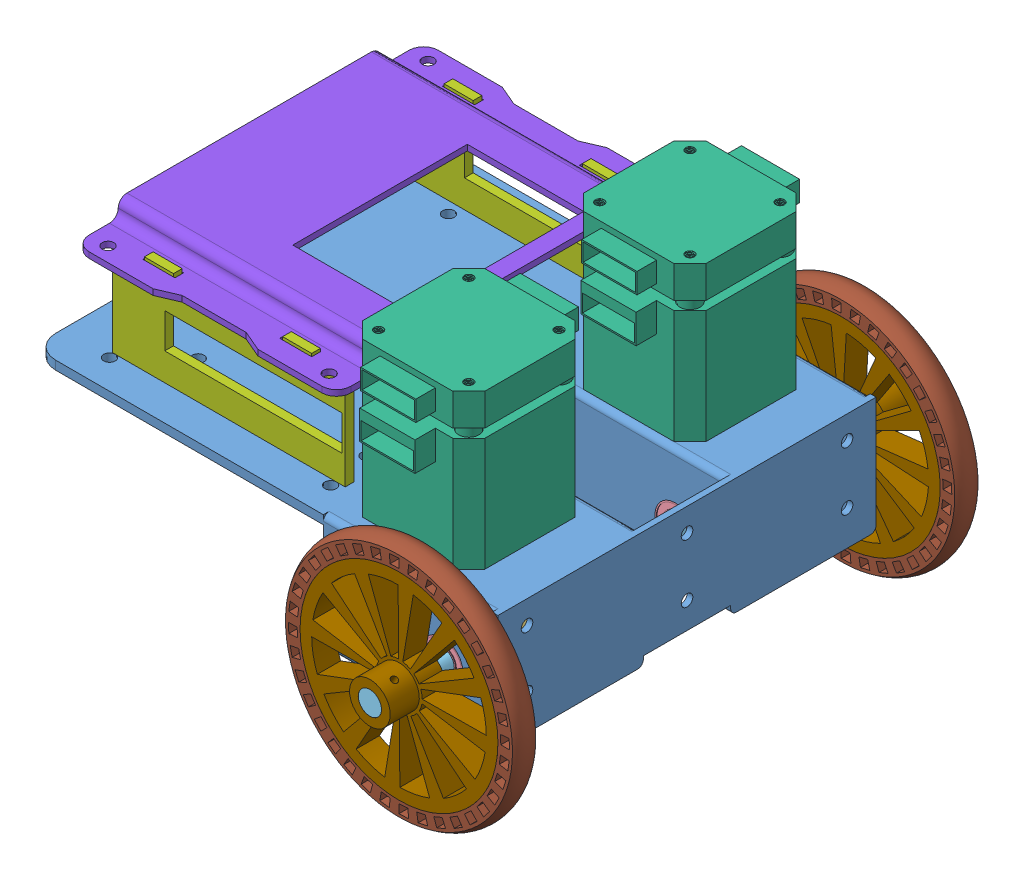
SolidWorks assembly JetBot, configuration 默认. Lengths in mm.
Overall size (187.31 122.31 180).
21 component instances, 11 part files, 44 mates.
Components (placement in the parent):
- Part_Frame_42Motor-1: Part_Frame_42Motor [默认] at (-18.89 -6.9833 215) size (160 40 130)
- Part_Shaft_1Modulus_1Teeth_42SMotor-1: Part_Shaft_1Modulus_1Teeth_42SMotor [默认] at (4.11 0.0167 268) x (0 1 0) z (0.917431 0 0.397896) size (33.1 17.69 17.84)
- Part_Turbine_1Modulus_20Teeth_42SMotor-1: Part_Turbine_1Modulus_20Teeth_42SMotor [默认] at (22.11 10.0167 197.3769) x (0.249686 -0.968327 0) z (0.968327 0.249686 0) size (29.84 18 44.58)
- Part_Shaft_1Modulus_1Teeth_42SMotor-2: Part_Shaft_1Modulus_1Teeth_42SMotor [默认] at (4.11 0.0167 192) x (0 1 0) z (0 0 1) size (33.1 17.69 17.84)
- Part_Turbine_1Modulus_20Teeth_42SMotor-2: Part_Turbine_1Modulus_20Teeth_42SMotor [默认] at (22.11 10.0167 262.7715) x (-0.761731 -0.647894 0) z (-0.647894 0.761731 0) size (29.84 18 44.58)
- Part_Bearing_MR148ZZ-1: Part_Bearing_MR148ZZ [默认] at (22.11 10.0167 249) x (0 0 -1) z (-0.338993 0.940789 0) size (4 14 14)
- Part_Bearing_MR148ZZ-2: Part_Bearing_MR148ZZ [默认] at (22.11 10.0167 215) x (0 0 -1) z (0.782637 0.622478 0) size (4 14 14)
- Part_Bearing_MR148ZZ-3: Part_Bearing_MR148ZZ [默认] at (22.11 10.0167 165) x (0 0 1) z (-0.469267 0.883056 0) size (4 14 14)
- Part_Bearing_MR148ZZ-4: Part_Bearing_MR148ZZ [默认] at (22.11 10.0167 291) x (0 0 1) z (-0.560257 0.828319 0) size (4 14 14)
- Part_Axis_8mm_Turbine_Wheel-1: Part_Axis_8mm_Turbine_Wheel [默认] at (22.11 10.0167 140) x (-0.226706 -0.973963 0) z (0 0 1) size (8 17.7 80)
- Part_Axis_8mm_Turbine_Wheel-2: Part_Axis_8mm_Turbine_Wheel [默认] at (22.11 10.0167 320) x (-0.923728 -0.383049 0) z (0 0 -1) size (8 17.7 80)
- Part_42Motor-2: Part_42Motor [默认] at (25.11 86.0167 213) x (-1 0 0) z (0 0 1) size (42 76 55.7)
- Part_Shell_Side_Frame-1: Part_Shell_Side_Frame [默认] at (-23.39 64.0167 177) x (-1 0 0) z (0 0 1) size (80 37 3)
- Part_Shell_Side_Frame-2: Part_Shell_Side_Frame [默认] at (-23.39 64.0167 280) x (-1 0 0) z (0 0 1) size (80 37 3)
- Part_Shell_Top_Frame-1: Part_Shell_Top_Frame [默认] at (-19.39 70.0167 230) x (0 0 1) z (-1 0 0) size (120 8 90)
- Part_42Motor-3: Part_42Motor [默认] at (25.11 86.0167 289) x (-1 0 0) z (0 0 1) size (42 76 55.7)
- Part_Wheel_Motor-1: Part_Wheel_Motor [默认] at (22.11 10.0167 306) x (0.490908 0.871211 0) z (0 0 1) size (68 68 18)
- Part_Wheel_Motor-2: Part_Wheel_Motor [默认] at (22.11 10.0167 154) x (-0.998325 0.057848 0) z (0 0 -1) size (68 68 18)
- Part_Wheel_Universal-1: Part_Wheel_Universal [默认] at (-81.89 -6.9833 230) x (0 0 -1) z (-1 0 0) size (28 21 48)
- Part_Tires_Wheel-1: Part_Tires_Wheel [默认] at (22.11 10.0167 306) size (80.81 80.81 8)
- Part_Tires_Wheel-2: Part_Tires_Wheel [默认] at (22.11 10.0167 154) size (80.81 80.81 8)
Mates (geometry in assembly coordinates):
- 同心2: concentric anti-aligned: cylinder of Part_Shaft_1Modulus_1Teeth_42SMotor-2 through (4.11 30.0167 192) axis (0 -1 0) radius 2.5; cylinder of Part_42Motor-2 through (4.11 10.0167 192) axis (0 1 0) radius 2.5
- 距离1: distance = 3 mm anti-aligned: plane of Part_Shaft_1Modulus_1Teeth_42SMotor-2 through (4.11 30.0167 192) normal (0 1 0); plane of Part_42Motor-2 through (25.11 33.0167 213) normal (0 -1 0)
- 同心3: concentric anti-aligned: cylinder of Part_Turbine_1Modulus_20Teeth_42SMotor-1 through (22.11 10.0167 187.3769) axis (0 0 1) radius 4; cylinder of Part_Axis_8mm_Turbine_Wheel-1 through (22.11 10.0167 220) axis (0 0 -1) radius 4
- 同心4: concentric anti-aligned: cylinder of Part_Turbine_1Modulus_20Teeth_42SMotor-2 through (22.11 10.0167 272.7715) axis (0 0 -1) radius 4; cylinder of Part_Axis_8mm_Turbine_Wheel-2 through (22.11 10.0167 240) axis (0 0 1) radius 4
- 同心5: concentric anti-aligned: cylinder of Part_Bearing_MR148ZZ-3 through (22.11 10.0167 169) axis (0 0 -1) radius 4; cylinder of Part_Axis_8mm_Turbine_Wheel-2 through (22.11 10.0167 240) axis (0 0 1) radius 4
- 同心6: concentric anti-aligned: cylinder of Part_Bearing_MR148ZZ-4 through (22.11 10.0167 295) axis (0 0 -1) radius 4; cylinder of Part_Axis_8mm_Turbine_Wheel-2 through (22.11 10.0167 240) axis (0 0 1) radius 4
- 同心7: concentric anti-aligned: cylinder of Part_Bearing_MR148ZZ-1 through (22.11 10.0167 245) axis (0 0 1) radius 4; cylinder of Part_Axis_8mm_Turbine_Wheel-1 through (22.11 10.0167 220) axis (0 0 -1) radius 4
- 同心8: concentric anti-aligned: cylinder of Part_Bearing_MR148ZZ-2 through (22.11 10.0167 211) axis (0 0 1) radius 4; cylinder of Part_Axis_8mm_Turbine_Wheel-1 through (22.11 10.0167 220) axis (0 0 -1) radius 4
- 同心9: concentric anti-aligned: cylinder of Part_Frame_42Motor-1 through (22.11 10.0167 165) axis (0 0 1) radius 7; cylinder of Part_Axis_8mm_Turbine_Wheel-1 through (22.11 10.0167 220) axis (0 0 -1) radius 4
- 同心10: concentric aligned: cylinder of Part_Frame_42Motor-1 through (22.11 10.0167 165) axis (0 0 1) radius 7; cylinder of Part_Axis_8mm_Turbine_Wheel-2 through (22.11 10.0167 240) axis (0 0 1) radius 4
- 重合3: coincident anti-aligned: plane of Part_Frame_42Motor-1 through (41.11 33.0167 167) normal (0 1 0); plane of Part_42Motor-2 through (25.11 33.0167 213) normal (0 -1 0)
- 重合5: coincident aligned: plane of Part_Frame_42Motor-1 through (41.11 -4.9833 165) normal (0 0 -1); plane of Part_Bearing_MR148ZZ-3 through (22.11 10.0167 165) normal (0 0 -1)
- 重合6: coincident aligned: plane of Part_Frame_42Motor-1 through (41.11 31.0167 215) normal (0 0 1); plane of Part_Bearing_MR148ZZ-2 through (22.11 10.0167 215) normal (0 0 1)
- 重合7: coincident aligned: plane of Part_Frame_42Motor-1 through (41.11 31.0167 245) normal (0 0 -1); plane of Part_Bearing_MR148ZZ-1 through (22.11 10.0167 245) normal (0 0 -1)
- 重合8: coincident aligned: plane of Part_Frame_42Motor-1 through (-18.89 30.0167 295) normal (0 0 1); plane of Part_Bearing_MR148ZZ-4 through (22.11 10.0167 295) normal (0 0 1)
- 距离3: distance = 5 mm aligned: plane of Part_Axis_8mm_Turbine_Wheel-2 through (22.11 10.0167 240) normal (0 0 -1); plane of Part_Frame_42Motor-1 through (41.11 31.0167 245) normal (0 0 -1)
- 距离4: distance = 5 mm aligned: plane of Part_Axis_8mm_Turbine_Wheel-1 through (22.11 10.0167 220) normal (0 0 1); plane of Part_Frame_42Motor-1 through (41.11 31.0167 215) normal (0 0 1)
- 同心11: concentric aligned: cylinder of Part_Frame_42Motor-1 through (4.11 -6.9843 192) axis (0 1 0) radius 12.5; cylinder of Part_42Motor-2 through (4.11 31.0167 192) axis (0 1 0) radius 11
- 同心12: concentric anti-aligned: cylinder of Part_Frame_42Motor-1 through (19.61 -6.9843 176.5) axis (0 1 0) radius 2.25; circle of Part_42Motor-2
- 重合9: coincident anti-aligned: plane of Part_Frame_42Motor-1 through (41.11 33.0167 167) normal (0 1 0); plane of Part_Shell_Side_Frame-1 through (-23.39 33.0167 180) normal (0 -1 0)
- 重合10: coincident anti-aligned: plane of Part_Frame_42Motor-1 through (-45.89 -6.9843 180) normal (0 0 -1); plane of Part_Shell_Side_Frame-1 through (-23.39 64.0167 180) normal (0 0 1)
- 重合11: coincident anti-aligned: plane of Part_Frame_42Motor-1 through (-34.89 -6.9843 177) normal (-1 0 0); plane of Part_Shell_Side_Frame-1 through (-34.89 33.0167 177) normal (1 0 0)
- 重合12: coincident anti-aligned: plane of Part_Frame_42Motor-1 through (41.11 33.0167 167) normal (0 1 0); plane of Part_Shell_Side_Frame-2 through (-23.39 33.0167 283) normal (0 -1 0)
- 重合13: coincident anti-aligned: plane of Part_Frame_42Motor-1 through (-81.89 -6.9843 283) normal (0 0 -1); plane of Part_Shell_Side_Frame-2 through (-23.39 64.0167 283) normal (0 0 1)
- 重合14: coincident aligned: plane of Part_Shell_Side_Frame-1 through (-92.39 64.0167 177) normal (-1 0 0); plane of Part_Shell_Side_Frame-2 through (-92.39 64.0167 280) normal (-1 0 0)
- 重合15: coincident anti-aligned: plane of Part_Shell_Side_Frame-1 through (-23.39 64.0167 180) normal (0 1 0); plane of Part_Shell_Top_Frame-1 through (-109.39 64.0167 187) normal (0 -1 0)
- 重合16: coincident anti-aligned: plane of Part_Shell_Side_Frame-1 through (-23.39 64.0167 180) normal (0 0 1); plane of Part_Shell_Top_Frame-1 through (-81.89 64.0167 180) normal (0 0 -1)
- 重合17: coincident anti-aligned: plane of Part_Shell_Side_Frame-1 through (-34.89 64.0167 177) normal (1 0 0); plane of Part_Shell_Top_Frame-1 through (-34.89 64.0167 180) normal (-1 0 0)
- 同心13: concentric anti-aligned: cylinder of Part_Shaft_1Modulus_1Teeth_42SMotor-1 through (4.11 30.0167 268) axis (0 -1 0) radius 2.5; cylinder of Part_42Motor-3 through (4.11 10.0167 268) axis (0 1 0) radius 2.5
- 同心14: concentric anti-aligned: cylinder of Part_Frame_42Motor-1 through (19.61 -6.9843 283.5) axis (0 1 0) radius 2.25; circle of Part_42Motor-3
- 重合18: coincident anti-aligned: plane of Part_Frame_42Motor-1 through (41.11 33.0167 167) normal (0 1 0); plane of Part_42Motor-3 through (25.11 33.0167 289) normal (0 -1 0)
- 同心15: concentric aligned: cylinder of Part_Frame_42Motor-1 through (4.11 -6.9843 268) axis (0 1 0) radius 12.5; cylinder of Part_42Motor-3 through (4.11 10.0167 268) axis (0 1 0) radius 2.5
- 距离5: distance = 3 mm anti-aligned: plane of Part_42Motor-3 through (25.11 33.0167 289) normal (0 -1 0); plane of Part_Shaft_1Modulus_1Teeth_42SMotor-1 through (4.11 30.0167 268) normal (0 1 0)
- 同心16: concentric aligned: cylinder of Part_Axis_8mm_Turbine_Wheel-2 through (22.11 10.0167 240) axis (0 0 1) radius 4; cylinder of Part_Wheel_Motor-1 through (22.11 10.0167 306) axis (0 0 1) radius 4
- 重合20: coincident anti-aligned: plane of Part_Frame_42Motor-1 through (-118.89 -6.9833 213) normal (0 -1 0); plane of Part_Wheel_Universal-1 through (-81.89 -6.9833 230) normal (0 1 0)
- 同心17: concentric anti-aligned: cylinder of Part_Frame_42Motor-1 through (-61.89 -3.9833 230) axis (0 -1 0) radius 1.5; cylinder of Part_Wheel_Universal-1 through (-61.89 -8.4833 230) axis (0 1 0) radius 2
- 同心18: concentric anti-aligned: cylinder of Part_Frame_42Motor-1 through (-101.89 -3.9833 230) axis (0 -1 0) radius 1.5; cylinder of Part_Wheel_Universal-1 through (-101.89 -8.4833 230) axis (0 1 0) radius 2
- 同心19: concentric aligned: cylinder of Part_Axis_8mm_Turbine_Wheel-1 through (22.11 10.0167 220) axis (0 0 -1) radius 4; cylinder of Part_Wheel_Motor-2 through (22.11 10.0167 154) axis (0 0 -1) radius 4
- 重合21: coincident aligned: plane of Part_Axis_8mm_Turbine_Wheel-1 through (22.11 10.0167 140) normal (0 0 -1); plane of Part_Wheel_Motor-2 through (26.1033 9.7853 140) normal (0 0 -1)
- 重合22: coincident aligned: plane of Part_Axis_8mm_Turbine_Wheel-2 through (22.11 10.0167 320) normal (0 0 1); plane of Part_Wheel_Motor-1 through (20.1464 6.5318 320) normal (0 0 1)
- 同心20: concentric anti-aligned: cylinder of Part_Wheel_Motor-2 through (22.11 10.0167 154) axis (0 0 -1) radius 34; cylinder of Part_Tires_Wheel-2 through (22.11 10.0167 154) axis (0 0 1) radius 34
- 重合23: coincident aligned: plane of Part_Wheel_Motor-2 through (26.1033 9.7853 158) normal (0 0 1); plane of Part_Tires_Wheel-2 through (-11.89 10.0167 158) normal (0 0 1)
- 同心21: concentric aligned: cylinder of Part_Wheel_Motor-1 through (22.11 10.0167 306) axis (0 0 1) radius 34; cylinder of Part_Tires_Wheel-1 through (22.11 10.0167 306) axis (0 0 1) radius 34
- 重合25: coincident aligned: plane of Part_Wheel_Motor-1 through (18.6736 3.9182 310) normal (0 0 1); plane of Part_Tires_Wheel-1 through (-11.89 10.0167 310) normal (0 0 1)
